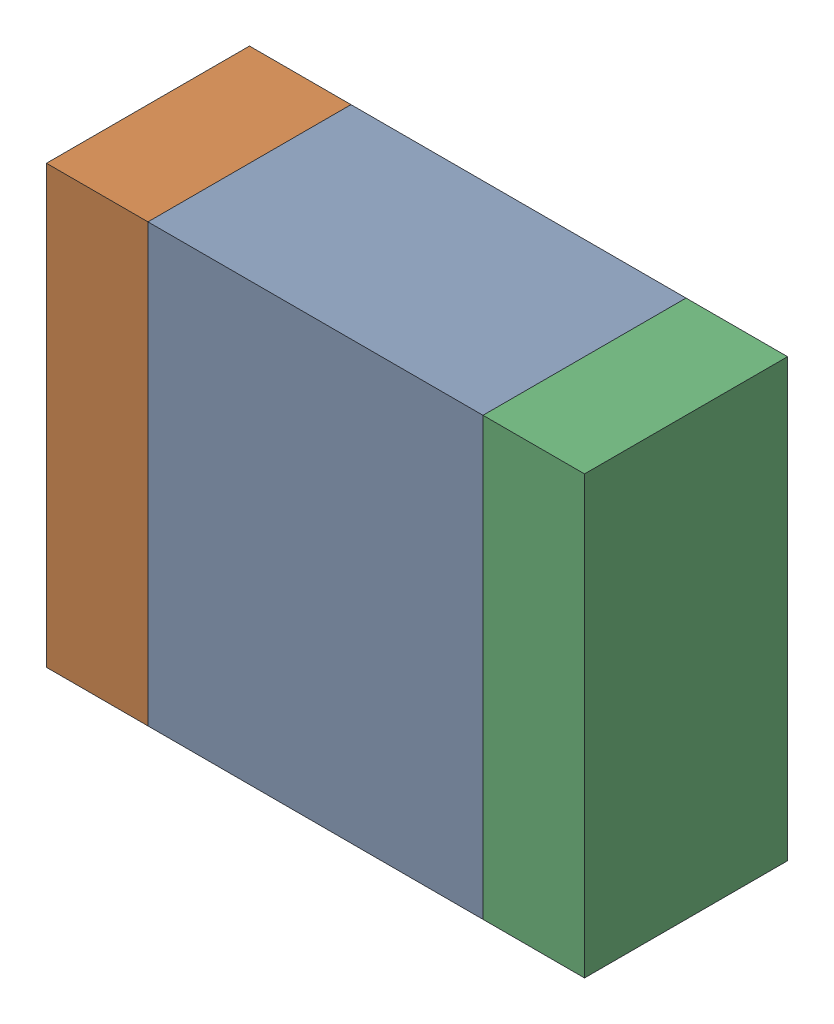
SolidWorks assembly L401PCB, configuration Default. Lengths in mm.
Overall size (2.65 2.15 1).
6 component instances, 2 part files, 0 mates.
Components (placement in the parent):
- 846486688-1: 846486688 [Default] at (78.59 87 0) size (1.65 2.15 1)
  - Extruded_25-1: Extruded_25 [Default] at origin size (1.65 2.15 1)
- 846486824-1: 846486824 [Default] at (77.515 87 0) size (0.5 2.15 1)
  - Extruded_26-1: Extruded_26 [Default] at origin size (0.5 2.15 1)
- 846486824-2: 846486824 [Default] at (79.665 87 0) size (0.5 2.15 1)
  - Extruded_26-1: Extruded_26 [Default] at origin size (0.5 2.15 1)
